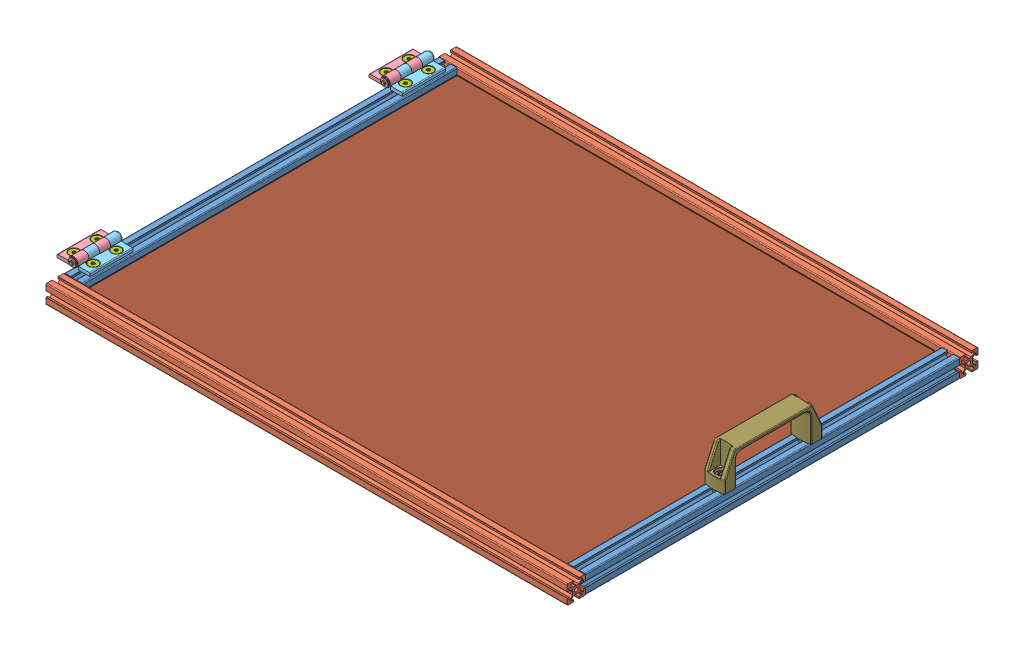
SolidWorks assembly Front_Door, configuration Default. Lengths in mm.
Overall size (591.06 58.1 447.5).
42 component instances, 13 part files, 70 mates.
Components (placement in the parent):
- HFS5-2020-407.5-1: HFS5-2020-407.5 [Default] at origin size (20 20 407.5)
- HFS5-2020-407.5-2: HFS5-2020-407.5 [Default] at (547.5 0 0) size (20 20 407.5)
- HFS5-2020-567.5-1: HFS5-2020-567.5 [Default] at (557.5 0 -417.5) x (0 0 -1) z (1 0 0) size (20 20 567.5)
- HFS5-2020-567.5-2: HFS5-2020-567.5 [Default] at (-10 0 10) x (0 0 1) z (-1 0 0) size (20 20 567.5)
- HHPSN5-1: HHPSN5 [Default] at (-10.5 15 -374) x (0.898485 0.439003 0) z (-0.439003 0.898485 0) size (36.74 53.4 24.79) (flexible)
  - HHPSN5-pin-1: HHPSN5-pin [Default] at origin size (4 53.4 4)
  - HHPSN5-l-1: HHPSN5-l [Default] x (0.898485 0 -0.439003) z (0.439003 0 0.898485) size (23 48.7 10)
  - HHPSN5-r-1: HHPSN5-r [Default] x (0.898485 0 -0.439003) z (0.439003 0 0.898485) size (23 48.7 10)
- HNTTSN5-5-1: HNTTSN5-5 [Default] at (-21 8.8 -361.5) x (0 1 0) z (0 0 1) size (4.3 10 10)
- HNTTSN5-5-2: HNTTSN5-5 [Default] at (-21 8.8 -386.5) x (0 1 0) z (0 0 -1) size (4.3 10 10)
- HNTTSN5-5-4: HNTTSN5-5 [Default] at (0 8.8 -361.5) x (0 1 0) z (0 0 1) size (4.3 10 10)
- HNTTSN5-5-8: HNTTSN5-5 [Default] at (0 8.8 -386.5) x (0 1 0) z (0 0 1) size (4.3 10 10)
- 5mmX10mm_Flathead(McMaster_91294A207)-3: 5mmX10mm_Flathead(McMaster_91294A207) [91294A207] at (-21 13.3 -361.5) x (0.898485 0 -0.439003) z (0 1 0) size (10 10 8.43)
- 5mmX10mm_Flathead(McMaster_91294A207)-5: 5mmX10mm_Flathead(McMaster_91294A207) [91294A207] at (0 13.3 -386.5) x (0.898485 0 -0.439003) z (0 1 0) size (10 10 8.43)
- 5mmX10mm_Flathead(McMaster_91294A207)-6: 5mmX10mm_Flathead(McMaster_91294A207) [91294A207] at (0 13.3 -361.5) x (0.898485 0 -0.439003) z (0 1 0) size (10 10 8.43)
- 5mmX10mm_Flathead(McMaster_91294A207)-8: 5mmX10mm_Flathead(McMaster_91294A207) [91294A207] at (-21 13.3 -386.5) x (0.898485 0 -0.439003) z (0 1 0) size (10 10 8.43)
- 5mmX10mm_Buttonhead(McMaster_91239A224)-1: 5mmX10mm_Buttonhead(McMaster_91239A224) [91239A224] at (547.5 0 4.75) size (9.5 9.5 13.21)
- 5mmX10mm_Buttonhead(McMaster_91239A224)-3: 5mmX10mm_Buttonhead(McMaster_91239A224) [91239A224] at (0 0 4.75) x (0.949227 -0.314592 0) z (0 0 1) size (9.5 9.5 13.21)
- 5mmX10mm_Buttonhead(McMaster_91239A224)-4: 5mmX10mm_Buttonhead(McMaster_91239A224) [91239A224] at (547.5 0 -412.25) x (-0.923728 -0.383049 0) z (0 0 -1) size (9.5 9.5 13.21)
- 5mmX10mm_Buttonhead(McMaster_91239A224)-7: 5mmX10mm_Buttonhead(McMaster_91239A224) [91239A224] at (0 0 -412.25) x (-0.616083 0.787681 0) z (0 0 -1) size (9.5 9.5 13.21)
- HNTTSN5-5-9: HNTTSN5-5 [Default] at (0 8.8 -21.5) x (0 1 0) z (0 0 1) size (4.3 10 10)
- HNTTSN5-5-10: HNTTSN5-5 [Default] at (0 8.8 -46.5) x (0 1 0) z (0 0 1) size (4.3 10 10)
- HNTTSN5-5-11: HNTTSN5-5 [Default] at (-21 8.8 -46.5) x (0 1 0) z (0 0 -1) size (4.3 10 10)
- HNTTSN5-5-12: HNTTSN5-5 [Default] at (-21 8.8 -21.5) x (0 1 0) z (0 0 1) size (4.3 10 10)
- HHPSN5-3: HHPSN5 [Default] at (-10.5 15 -34) x (0.898485 0.439003 0) z (-0.439003 0.898485 0) size (36.74 53.4 24.79) (flexible)
  - HHPSN5-pin-1: HHPSN5-pin [Default] at origin size (4 53.4 4)
  - HHPSN5-l-1: HHPSN5-l [Default] x (0.898485 0 -0.439003) z (0.439003 0 0.898485) size (23 48.7 10)
  - HHPSN5-r-1: HHPSN5-r [Default] x (0.898485 0 -0.439003) z (0.439003 0 0.898485) size (23 48.7 10)
- 5mmX10mm_Flathead(McMaster_91294A207)-9: 5mmX10mm_Flathead(McMaster_91294A207) [91294A207] at (-21 13.3 -21.5) x (0.898485 0 -0.439003) z (0 1 0) size (10 10 8.43)
- 5mmX10mm_Flathead(McMaster_91294A207)-10: 5mmX10mm_Flathead(McMaster_91294A207) [91294A207] at (0 13.3 -46.5) x (0.898485 0 -0.439003) z (0 1 0) size (10 10 8.43)
- 5mmX10mm_Flathead(McMaster_91294A207)-11: 5mmX10mm_Flathead(McMaster_91294A207) [91294A207] at (0 13.3 -21.5) x (0.898485 0 -0.439003) z (0 1 0) size (10 10 8.43)
- 5mmX10mm_Flathead(McMaster_91294A207)-12: 5mmX10mm_Flathead(McMaster_91294A207) [91294A207] at (-21 13.3 -46.5) x (0.898485 0 -0.439003) z (0 1 0) size (10 10 8.43)
- HSCA5-R_537.5mm-1: HSCA5-R_537.5mm [Default] at (273.75 0 0.1) x (0 1 0) z (1 0 0) size (7.2 5.9 533.5)
- HSCA5-R_537.5mm-2: HSCA5-R_537.5mm [Default] at (273.75 0 -407.6) x (0 1 0) z (-1 0 0) size (7.2 5.9 533.5)
- HSCA5-R_407.5mm-1: HSCA5-R_407.5mm [Default] at (9.9 0 -203.75) x (0 1 0) z (0 0 1) size (7.2 5.9 407.5)
- HSCA5-R_407.5mm-2: HSCA5-R_407.5mm [Default] at (537.6 -0.5196 -203.75) x (0 -1 0) z (0 0 1) size (7.2 5.9 407.5)
- Acrylic_or_Polycarbonate_Door_Window-1: Acrylic_or_Polycarbonate_Door_Window [Default] at (273.75 0 -203.75) x (1 0 0) z (0 -1 0) size (536 416 4.5)
- Handle_(McMaster_1078A311)-1: Handle_(McMaster_1078A311) [1078A311] at (547.5 10 -203.75) x (0 0 1) z (0 -1 0) size (110.14 22.23 38.1)
- 5mmX12mm_Sockethead(McMaster_92290A228)-1: 5mmX12mm_Sockethead(McMaster_92290A228) [92290A228] at (547.5 4 -156.9187) x (1 0 0) z (0 -1 0) size (8.5 8.5 17.93)
- 5mmX12mm_Sockethead(McMaster_92290A228)-2: 5mmX12mm_Sockethead(McMaster_92290A228) [92290A228] at (547.5 4 -250.5812) x (1 0 0) z (0 -1 0) size (8.5 8.5 17.93)
- HNTTSN5-5-13: HNTTSN5-5 [Default] at (547.5 8.8 -250.5812) x (0 1 0) z (0 0 1) size (4.3 10 10)
- HNTTSN5-5-14: HNTTSN5-5 [Default] at (547.5 8.8 -156.9187) x (0 1 0) z (0 0 1) size (4.3 10 10)
Mates (geometry in assembly coordinates):
- Concentric1: concentric aligned: cylinder of HFS5-2020-407.5-1 through (0 0 -407.5) axis (0 0 1) radius 2.1; cylinder of 5mmX10mm_Buttonhead(McMaster_91239A224)-3 through (0 0 4.75) axis (0 0 1) radius 4.75
- Distance1: distance = 2 mm anti-aligned: plane of HFS5-2020-407.5-1 through (-9 9 0) normal (0 0 1); plane of 5mmX10mm_Buttonhead(McMaster_91239A224)-3 through (-1.4943 -4.5088 2) normal (0 0 -1)
- Concentric2: concentric anti-aligned: cylinder of HFS5-2020-407.5-1 through (0 0 -407.5) axis (0 0 1) radius 2.1; cylinder of 5mmX10mm_Buttonhead(McMaster_91239A224)-7 through (0 0 -412.25) axis (0 0 -1) radius 4.75
- Distance2: distance = 2 mm anti-aligned: plane of HFS5-2020-407.5-1 through (-9 9 -407.5) normal (0 0 -1); plane of 5mmX10mm_Buttonhead(McMaster_91239A224)-7 through (-3.7415 -2.9264 -409.5) normal (0 0 1)
- Concentric3: concentric aligned: cylinder of HFS5-2020-407.5-2 through (547.5 0 -407.5) axis (0 0 1) radius 2.1; cylinder of 5mmX10mm_Buttonhead(McMaster_91239A224)-1 through (547.5 0 4.75) axis (0 0 1) radius 4.75
- Distance3: distance = 2 mm anti-aligned: plane of HFS5-2020-407.5-2 through (538.5 9 0) normal (0 0 1); plane of 5mmX10mm_Buttonhead(McMaster_91239A224)-1 through (547.5 -4.75 2) normal (0 0 -1)
- Concentric4: concentric anti-aligned: cylinder of HFS5-2020-407.5-2 through (547.5 0 -407.5) axis (0 0 1) radius 2.1; cylinder of 5mmX10mm_Buttonhead(McMaster_91239A224)-4 through (547.5 0 -412.25) axis (0 0 -1) radius 4.75
- Distance4: distance = 2 mm anti-aligned: plane of HFS5-2020-407.5-2 through (538.5 9 -407.5) normal (0 0 -1); plane of 5mmX10mm_Buttonhead(McMaster_91239A224)-4 through (549.3195 -4.3877 -409.5) normal (0 0 1)
- Concentric5: concentric aligned: cylinder of HFS5-2020-567.5-2 through (0 0 -1.0711) axis (0 0 1) radius 2.5; cylinder of 5mmX10mm_Buttonhead(McMaster_91239A224)-3 through (0 0 4.75) axis (0 0 1) radius 4.75
- Coincident5: coincident anti-aligned: plane of HFS5-2020-407.5-1 through (-9 9 0) normal (0 0 1); plane of HFS5-2020-567.5-2 through (557.5 9 0) normal (0 0 -1)
- Coincident6: coincident aligned: plane of HFS5-2020-407.5-1 through (9 10 -407.5) normal (0 1 0); plane of HFS5-2020-567.5-2 through (557.5 10 6.7) normal (0 1 0)
- Concentric6: concentric aligned: cylinder of HFS5-2020-567.5-1 through (0 0 -406.4289) axis (0 0 -1) radius 2.5; cylinder of 5mmX10mm_Buttonhead(McMaster_91239A224)-7 through (0 0 -412.25) axis (0 0 -1) radius 4.75
- Coincident7: coincident anti-aligned: plane of HFS5-2020-407.5-1 through (-9 9 -407.5) normal (0 0 -1); plane of HFS5-2020-567.5-1 through (-10 9 -407.5) normal (0 0 1)
- Coincident8: coincident aligned: plane of HFS5-2020-407.5-1 through (9 10 -407.5) normal (0 1 0); plane of HFS5-2020-567.5-1 through (-10 10 -414.2) normal (0 1 0)
- Concentric7: concentric aligned: cylinder of HFS5-2020-567.5-2 through (547.5 0 -1.0711) axis (0 0 1) radius 2.5; cylinder of 5mmX10mm_Buttonhead(McMaster_91239A224)-1 through (547.5 0 4.75) axis (0 0 1) radius 4.75
- Coincident9: coincident anti-aligned: plane of HFS5-2020-407.5-2 through (538.5 9 0) normal (0 0 1); plane of HFS5-2020-567.5-2 through (557.5 9 0) normal (0 0 -1)
- Coincident10: coincident aligned: plane of HFS5-2020-407.5-2 through (544.2 10 -407.5) normal (0 1 0); plane of HFS5-2020-567.5-2 through (557.5 10 6.7) normal (0 1 0)
- Concentric8: concentric aligned: cylinder of HFS5-2020-567.5-1 through (547.5 0 -406.4289) axis (0 0 -1) radius 2.5; cylinder of 5mmX10mm_Buttonhead(McMaster_91239A224)-4 through (547.5 0 -412.25) axis (0 0 -1) radius 4.75
- Concentric9: concentric anti-aligned: cylinder of HHPSN5-1/HHPSN5-r-1 through (0 13.5 -361.5) axis (0 -1 0) radius 2.75; cylinder of 5mmX10mm_Flathead(McMaster_91294A207)-6 through (0 13.3 -361.5) axis (0 1 0) radius 5
- Coincident11: coincident aligned: cone of HHPSN5-1/HHPSN5-r-1 through (0 13.5 -361.5) axis (0 -1 0); cone of 5mmX10mm_Flathead(McMaster_91294A207)-6 through (0 10.5 -361.5) axis (0 -1 0)
- Concentric10: concentric anti-aligned: cylinder of HHPSN5-1/HHPSN5-l-1 through (-21 13.5 -361.5) axis (0 -1 0) radius 2.75; cylinder of 5mmX10mm_Flathead(McMaster_91294A207)-3 through (-21 13.3 -361.5) axis (0 1 0) radius 5
- Coincident12: coincident aligned: cone of HHPSN5-1/HHPSN5-l-1 through (-21 13.5 -361.5) axis (0 -1 0); cone of 5mmX10mm_Flathead(McMaster_91294A207)-3 through (-21 10.5 -361.5) axis (0 -1 0)
- Concentric11: concentric anti-aligned: cylinder of HHPSN5-1/HHPSN5-r-1 through (0 13.5 -386.5) axis (0 -1 0) radius 2.75; cylinder of 5mmX10mm_Flathead(McMaster_91294A207)-5 through (0 13.3 -386.5) axis (0 1 0) radius 5
- Coincident13: coincident aligned: cone of HHPSN5-1/HHPSN5-r-1 through (0 13.5 -386.5) axis (0 -1 0); cone of 5mmX10mm_Flathead(McMaster_91294A207)-5 through (0 10.5 -386.5) axis (0 -1 0)
- Concentric12: concentric anti-aligned: cylinder of HHPSN5-1/HHPSN5-l-1 through (-21 13.5 -386.5) axis (0 -1 0) radius 2.75; cylinder of 5mmX10mm_Flathead(McMaster_91294A207)-8 through (-21 13.3 -386.5) axis (0 1 0) radius 5
- Coincident14: coincident aligned: cone of HHPSN5-1/HHPSN5-l-1 through (-21 13.5 -386.5) axis (0 -1 0); cone of 5mmX10mm_Flathead(McMaster_91294A207)-8 through (-21 10.5 -386.5) axis (0 -1 0)
- Concentric13: concentric aligned: cylinder of HHPSN5-1/HHPSN5-l-1 through (-21 13.5 -386.5) axis (0 -1 0) radius 2.75; cylinder of HNTTSN5-5-2 through (-21 8.8 -386.5) axis (0 -1 0) radius 2.067
- Distance5: distance = 2 mm anti-aligned: plane of HNTTSN5-5-2 through (-18.1 8 -391.5) normal (0 1 0); plane of HHPSN5-1/HHPSN5-l-1 through (-10.5 10 -374) normal (0 -1 0)
- Parallel1: parallel anti-aligned: plane of HHPSN5-1/HHPSN5-l-1 through (-10.5 15 -397.5) normal (0 0 -1); plane of HNTTSN5-5-2 through (-21 8.8 -381.5) normal (0 0 1)
- Concentric14: concentric aligned: cylinder of HHPSN5-1/HHPSN5-r-1 through (0 13.5 -386.5) axis (0 -1 0) radius 2.75; cylinder of HNTTSN5-5-8 through (0 8.8 -386.5) axis (0 -1 0) radius 2.067
- Parallel2: parallel aligned: plane of HNTTSN5-5-8 through (0 8.8 -391.5) normal (0 0 -1); plane of HHPSN5-1/HHPSN5-l-1 through (-10.5 15 -397.5) normal (0 0 -1)
- Distance6: distance = 2 mm anti-aligned: plane of HNTTSN5-5-8 through (5 8 -381.5) normal (0 1 0); plane of HHPSN5-1/HHPSN5-r-1 through (-10.5 10 -374) normal (0 -1 0)
- Concentric15: concentric aligned: cylinder of HHPSN5-1/HHPSN5-l-1 through (-21 13.5 -361.5) axis (0 -1 0) radius 2.75; cylinder of HNTTSN5-5-1 through (-21 8.8 -361.5) axis (0 -1 0) radius 2.067
- Parallel3: parallel aligned: plane of HHPSN5-1/HHPSN5-l-1 through (-10.5 15 -397.5) normal (0 0 -1); plane of HNTTSN5-5-1 through (-21 8.8 -366.5) normal (0 0 -1)
- Distance7: distance = 2 mm anti-aligned: plane of HHPSN5-1/HHPSN5-l-1 through (-10.5 10 -374) normal (0 -1 0); plane of HNTTSN5-5-1 through (-23.9 8 -356.5) normal (0 1 0)
- Concentric16: concentric aligned: cylinder of HHPSN5-1/HHPSN5-r-1 through (0 13.5 -361.5) axis (0 -1 0) radius 2.75; cylinder of HNTTSN5-5-4 through (0 8.8 -361.5) axis (0 -1 0) radius 2.067
- Parallel4: parallel aligned: plane of HHPSN5-1/HHPSN5-l-1 through (-10.5 15 -397.5) normal (0 0 -1); plane of HNTTSN5-5-4 through (0 8.8 -366.5) normal (0 0 -1)
- Distance8: distance = 2 mm anti-aligned: plane of HHPSN5-1/HHPSN5-r-1 through (-10.5 10 -374) normal (0 -1 0); plane of HNTTSN5-5-4 through (-2.9 8 -356.5) normal (0 1 0)
- Coincident24: coincident anti-aligned: plane of HFS5-2020-407.5-1 through (9 10 -407.5) normal (0 1 0); plane of HHPSN5-1/HHPSN5-r-1 through (-10.5 10 -374) normal (0 -1 0)
- Distance9: distance = 30 mm aligned: plane of HHPSN5-1/HHPSN5-r-1 through (-10.5 15 -397.5) normal (0 0 -1); plane of HFS5-2020-567.5-1 through (-10 3.3 -427.5) normal (0 0 -1)
- Distance10: distance = 2.5 mm aligned: plane of HHPSN5-1/HHPSN5-r-1 through (7.5 13.5 -350.5) normal (1 0 0); plane of HFS5-2020-407.5-1 through (10 3.3 -407.5) normal (1 0 0)
- Coincident28: coincident aligned: plane of HHPSN5-1/HHPSN5-l-1 through (-10.5 13.5 -374) normal (0 1 0); plane of ? through (-10.5 13.5 -34) normal (0 1 0)
- Coincident29: coincident anti-aligned: plane of HFS5-2020-567.5-1 through (-10 -0.5196 -413.5) normal (0 0 1); plane of HSCA5-R_537.5mm-2 through (7 2.4868 -413.5) normal (0 0 -1)
- Coincident30: coincident anti-aligned: plane of HFS5-2020-567.5-1 through (273.75 0 -417.5) normal (1 0 0); plane of HSCA5-R_537.5mm-2 through (273.75 0 -407.6) normal (-1 0 0)
- Coincident31: coincident: line of HFS5-2020-567.5-1 through (2.5 0 -413.8) axis (1 0 0); plane of HSCA5-R_537.5mm-2
- Coincident32: coincident anti-aligned: plane of HFS5-2020-567.5-2 through (557.5 -0.5196 6) normal (0 0 -1); plane of HSCA5-R_537.5mm-1 through (540.5 2.4868 6) normal (0 0 1)
- Coincident33: coincident: line of HFS5-2020-567.5-2 through (545 0 6.3) axis (-1 0 0); plane of HSCA5-R_537.5mm-1
- Coincident34: coincident anti-aligned: plane of HFS5-2020-567.5-2 through (273.75 0 10) normal (-1 0 0); plane of HSCA5-R_537.5mm-1 through (273.75 0 0.1) normal (1 0 0)
- Coincident35: coincident anti-aligned: plane of HFS5-2020-407.5-1 through (4 -2.9393 -407.5) normal (1 0 0); plane of HSCA5-R_407.5mm-1 through (4 2.4868 0) normal (-1 0 0)
- Coincident36: coincident aligned: plane of HFS5-2020-407.5-1 through (0 0 -203.75) normal (0 0 1); plane of HSCA5-R_407.5mm-1 through (9.9 0 -203.75) normal (0 0 1)
- Coincident37: coincident: line of HFS5-2020-407.5-1 through (3.7 0 -407.5) axis (0 0 1); plane of HSCA5-R_407.5mm-1
- Coincident38: coincident anti-aligned: plane of HFS5-2020-407.5-2 through (543.5 -0.5196 -407.5) normal (-1 0 0); plane of HSCA5-R_407.5mm-2 through (543.5 -3.0064 0) normal (1 0 0)
- Coincident39: coincident aligned: plane of HFS5-2020-407.5-2 through (547.5 0 -203.75) normal (0 0 1); plane of HSCA5-R_407.5mm-2 through (537.6 -0.5196 -203.75) normal (0 0 1)
- Coincident40: coincident: line of HFS5-2020-407.5-2 through (543.5 -0.5196 -407.5) axis (0 0 1); plane of HSCA5-R_407.5mm-2
- Coincident41: coincident anti-aligned: plane of Acrylic_or_Polycarbonate_Door_Window-1 through (273.75 0 -203.75) normal (0 -1 0); plane of assembly through (0 0 0) normal (0 1 0)
- Coincident42: coincident anti-aligned: plane of Acrylic_or_Polycarbonate_Door_Window-1 through (273.75 0 -203.75) normal (0 0 1); plane of assembly through (0 0 -203.75) normal (0 0 -1)
- Coincident43: coincident anti-aligned: plane of Acrylic_or_Polycarbonate_Door_Window-1; plane of assembly through (273.75 0 0) normal (-1 0 0)
- Concentric17: concentric aligned: cylinder of Handle_(McMaster_1078A311)-1 through (547.5 16 -250.5812) axis (0 -1 0) radius 3.25; cylinder of 5mmX12mm_Sockethead(McMaster_92290A228)-2 through (547.5 21 -250.5812) axis (0 -1 0) radius 4.25
- Coincident44: coincident anti-aligned: plane of Handle_(McMaster_1078A311)-1 through (547.5 16 -250.5812) normal (0 1 0); plane of 5mmX12mm_Sockethead(McMaster_92290A228)-2 through (547.5 16 -250.5812) normal (0 -1 0)
- Concentric18: concentric aligned: cylinder of Handle_(McMaster_1078A311)-1 through (547.5 16 -156.9187) axis (0 -1 0) radius 3.25; cylinder of 5mmX12mm_Sockethead(McMaster_92290A228)-1 through (547.5 21 -156.9187) axis (0 -1 0) radius 4.25
- Coincident45: coincident anti-aligned: plane of Handle_(McMaster_1078A311)-1 through (547.5 16 -156.9187) normal (0 1 0); plane of 5mmX12mm_Sockethead(McMaster_92290A228)-1 through (547.5 16 -156.9187) normal (0 -1 0)
- Concentric19: concentric aligned: cylinder of Handle_(McMaster_1078A311)-1 through (547.5 16 -156.9187) axis (0 -1 0) radius 3.25; cylinder of HNTTSN5-5-14 through (547.5 8.8 -156.9187) axis (0 -1 0) radius 2.067
- Perpendicular1: perpendicular: plane of Handle_(McMaster_1078A311)-1 through (536.3875 36.9875 -238.4845) normal (-1 0 0); plane of HNTTSN5-5-14 through (547.5 8.8 -151.9187) normal (0 0 1)
- Concentric20: concentric aligned: cylinder of Handle_(McMaster_1078A311)-1 through (547.5 16 -250.5812) axis (0 -1 0) radius 3.25; cylinder of HNTTSN5-5-13 through (547.5 8.8 -250.5812) axis (0 -1 0) radius 2.067
- Perpendicular2: perpendicular: plane of Handle_(McMaster_1078A311)-1 through (536.3875 36.9875 -238.4845) normal (-1 0 0); plane of HNTTSN5-5-13 through (547.5 8.8 -245.5813) normal (0 0 1)
- Distance11: distance = 2 mm anti-aligned: plane of Handle_(McMaster_1078A311)-1 through (536.3875 10 -243.247) normal (0 -1 0); plane of HNTTSN5-5-13 through (544.6 8 -245.5813) normal (0 1 0)
- Distance12: distance = 2 mm anti-aligned: plane of HNTTSN5-5-14 through (544.6 8 -151.9187) normal (0 1 0); plane of Handle_(McMaster_1078A311)-1 through (536.3875 10 -164.253) normal (0 -1 0)
- Coincident50: coincident anti-aligned: plane of HFS5-2020-407.5-2 through (556.5 10 -407.5) normal (0 1 0); plane of Handle_(McMaster_1078A311)-1 through (536.3875 10 -164.253) normal (0 -1 0)
- Coincident51: coincident anti-aligned: plane of HFS5-2020-407.5-2 through (547.5 0 0) normal (1 0 0); plane of Handle_(McMaster_1078A311)-1
- Coincident52: coincident aligned: plane of HSCA5-R_407.5mm-2 through (537.6 -0.5196 -203.75) normal (0 0 1); plane of Handle_(McMaster_1078A311)-1
